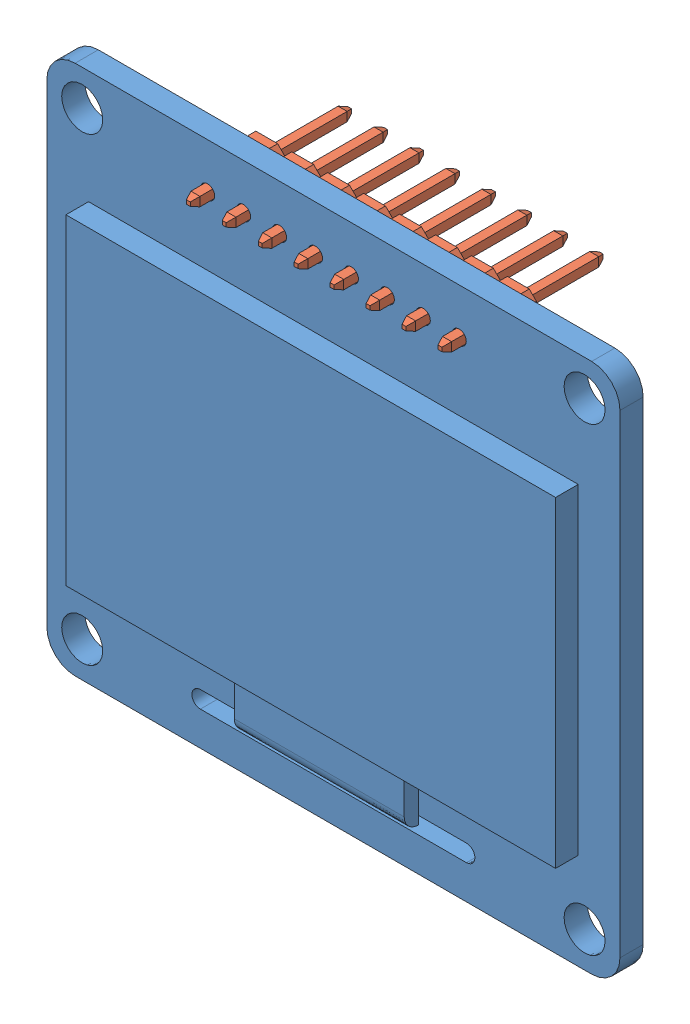
SolidWorks assembly OLED_1.3inch_sh1106, configuration Default. Lengths in mm.
Overall size (135.58 159.2 11.64).
9 component instances, 2 part files, 3 mates.
Components (placement in the parent):
- OLED_pcb_1.3-1: OLED_pcb_1.3 [Default] at (-11.6147 51.3978 113.1661) size (135.58 159.2 3.24)
- 2.54mm_pin_header-1: 2.54mm_pin_header [Default] at (-2.7247 66.9478 113.1661) x (-1 0 0) z (0 0 -1) size (2.54 2.5 11.4)
- 2.54mm_pin_header-2: 2.54mm_pin_header [Default] at (-5.2647 66.9478 113.1661) x (-1 0 0) z (0 0 -1) size (2.54 2.5 11.4)
- 2.54mm_pin_header-3: 2.54mm_pin_header [Default] at (-7.8047 66.9478 113.1661) x (-1 0 0) z (0 0 -1) size (2.54 2.5 11.4)
- 2.54mm_pin_header-4: 2.54mm_pin_header [Default] at (-10.3447 66.9478 113.1661) x (-1 0 0) z (0 0 -1) size (2.54 2.5 11.4)
- 2.54mm_pin_header-5: 2.54mm_pin_header [Default] at (-12.8847 66.9478 113.1661) x (-1 0 0) z (0 0 -1) size (2.54 2.5 11.4)
- 2.54mm_pin_header-6: 2.54mm_pin_header [Default] at (-15.4247 66.9478 113.1661) x (-1 0 0) z (0 0 -1) size (2.54 2.5 11.4)
- 2.54mm_pin_header-7: 2.54mm_pin_header [Default] at (-17.9647 66.9478 113.1661) x (-1 0 0) z (0 0 -1) size (2.54 2.5 11.4)
- 2.54mm_pin_header-8: 2.54mm_pin_header [Default] at (-20.5047 66.9478 113.1661) x (-1 0 0) z (0 0 -1) size (2.54 2.5 11.4)
Mates (geometry in assembly coordinates):
- Coincident1: coincident anti-aligned: plane of OLED_pcb_1.3-1 through (-11.6147 51.3978 113.1661) normal (0 0 -1); plane of 2.54mm_pin_header-1 through (-2.7247 66.9478 113.1661) normal (0 0 1)
- Coincident2: coincident aligned: cylinder of OLED_pcb_1.3-1 through (-2.7247 66.9478 113.1651) axis (0 0 1) radius 0.5; circle of 2.54mm_pin_header-1
- Parallel1: parallel aligned: plane of OLED_pcb_1.3-1 through (-31.8647 70.1478 114.8061) normal (0 1 0); plane of 2.54mm_pin_header-1 through (-1.4547 68.1978 110.6261) normal (0 1 0)
